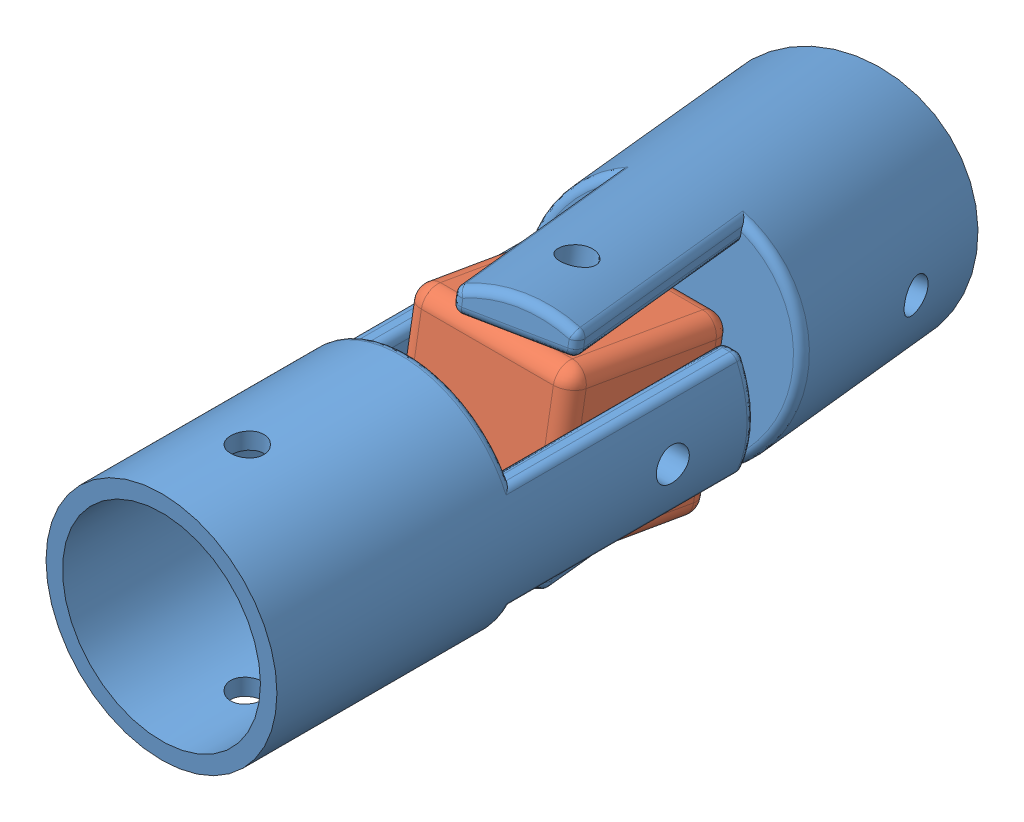
SolidWorks assembly Assemblage2, configuration Défaut. Lengths in mm.
Overall size (20.79 19.19 49.82).
3 component instances, 2 part files, 4 mates.
Components (placement in the parent):
- Pièce7_Articulation_4D-1: Pièce7_Articulation_4D [Défaut] at origin size (14 14 29)
- Pièce7_Articulation_4D-2: Pièce7_Articulation_4D [Défaut] at (-2.2436 -1.4881 -17.5879) x (0 0.985316 -0.170739) z (-0.249291 -0.165349 -0.954209) size (14 14 29)
- Pièce7_Articulation2_4D-1: Pièce7_Articulation2_4D [Défaut] at (0 4.9266 -9.8537) x (1 0 0) z (0 -0.985316 0.170739) size (10 10 10)
Mates (geometry in assembly coordinates):
- Coaxiale1: concentric anti-aligned: cylinder of Pièce7_Articulation_4D-1 through (9 0 -9) axis (-1 0 0) radius 1.0001; cylinder of Pièce7_Articulation2_4D-1 through (-5 0 -9) axis (1 0 0) radius 1
- Coïncidente1: coincident anti-aligned: plane of Pièce7_Articulation_4D-1 through (5 0 -14) normal (-1 0 0); plane of Pièce7_Articulation2_4D-1 through (5 -5.7803 -13.0729) normal (1 0 0)
- Coaxiale2: concentric anti-aligned: cylinder of Pièce7_Articulation_4D-2 through (0 8.8678 -10.5367) axis (0 -0.985316 0.170739) radius 1.0001; cylinder of Pièce7_Articulation2_4D-1 through (0 -4.9266 -8.1463) axis (0 0.985316 -0.170739) radius 1
- Coïncidente3: coincident anti-aligned: plane of Pièce7_Articulation_4D-2 through (1.2465 -4.0998 -3.3753) normal (0 0.985316 -0.170739); plane of Pièce7_Articulation2_4D-1 through (0 -4.9266 -8.1463) normal (0 -0.985316 0.170739)
